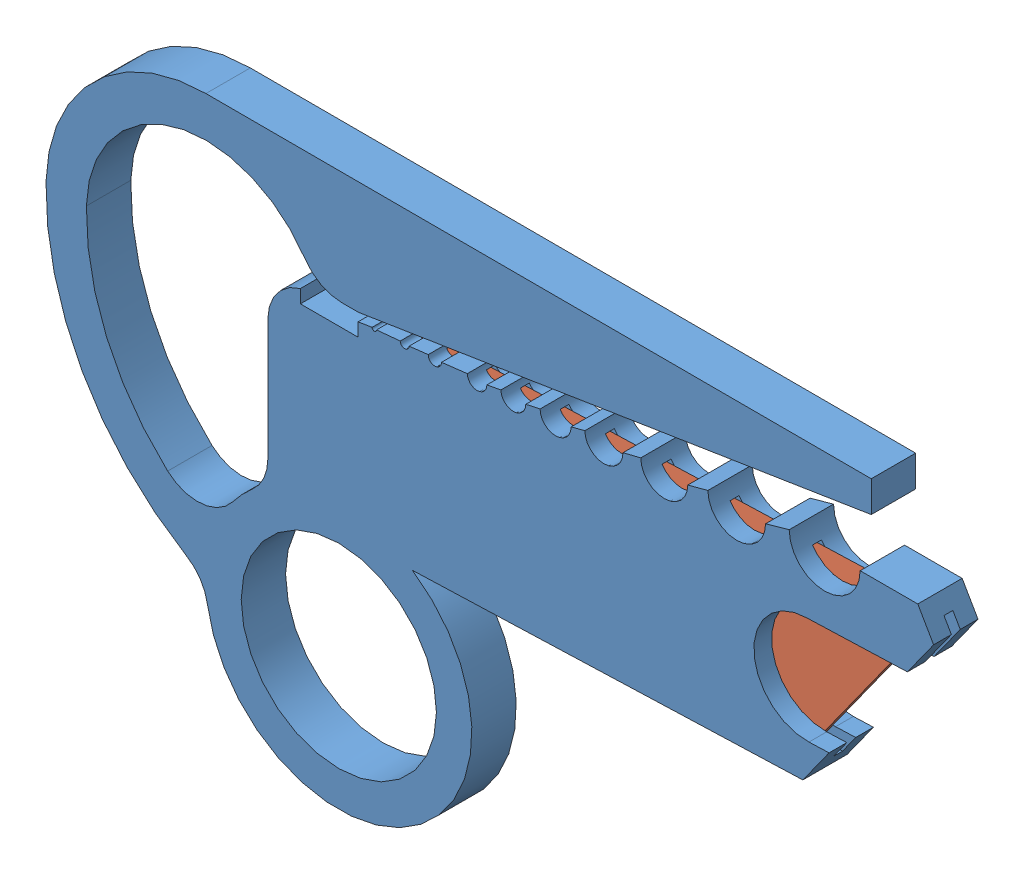
SolidWorks assembly Wire Stripper Assy, configuration Default. Lengths in mm.
Overall size (100.03 62.39 5).
2 component instances, 2 part files, 2 mates.
Components (placement in the parent):
- Wire Stripper-1: Wire Stripper [Default] at (-14.5156 45.9316 97.8127) size (100.03 62.39 5)
- Blade-1: Blade [Default] at (20.0865 80.8635 97.8127) x (-0.999391 -0.034899 0) z (0 0 1) size (62 19 0.6)
Mates (geometry in assembly coordinates):
- Coincident3: coincident aligned: plane of Wire Stripper-1 through (-14.5156 45.9316 97.8127) normal (0 0 1); plane of Blade-1 through (20.0865 80.8635 97.8127) normal (0 0 1)
- Distance2: distance = 2.5 mm aligned: plane of Wire Stripper-1 through (-14.9415 58.1272 100.3127) normal (0.034899 -0.999391 0); plane of Blade-1 through (15.3778 61.6875 98.1127) normal (0.034899 -0.999391 0)
